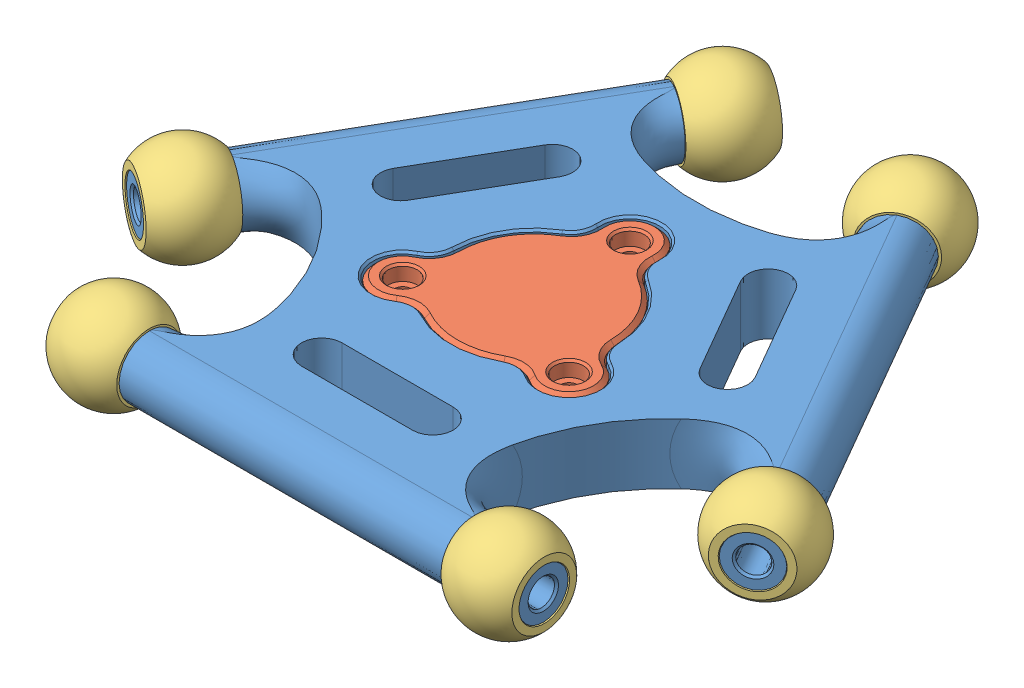
SolidWorks assembly flange, configuration Default. Lengths in mm.
Overall size (140.68 41.57 122.81).
8 component instances, 3 part files, 7 mates.
Components (placement in the parent):
- flange-star-1: flange-star [Default] at origin size (130.67 31.15 114.22)
- calibration-pin-1: calibration-pin [Default] at (0 12 0) x (-1 0 0) z (0 0 1) size (44.16 32 40.5)
- distal-link-sphere-1: distal-link-sphere [Default] at (39.1 5.9539 44.0446) x (0 -0.999016 0.044354) z (0 0.044354 0.999016) size (19 14 19)
- distal-link-sphere-2: distal-link-sphere [Default] at (-39.1 5.9539 44.0446) x (0 -0.979762 0.200167) z (0 0.200167 0.979762) size (19 14 19)
- distal-link-sphere-3: distal-link-sphere [Default] at (57.6937 5.9539 11.8393) x (0.173349 -0.979762 -0.100083) z (0.848499 0.200167 -0.489881) size (19 14 19)
- distal-link-sphere-4: distal-link-sphere [Default] at (-18.5937 5.9539 -55.8839) x (-0.173349 -0.979762 -0.100083) z (-0.848499 0.200167 -0.489881) size (19 14 19)
- distal-link-sphere-5: distal-link-sphere [Default] at (18.5937 5.9539 -55.8839) x (0.038412 -0.999016 -0.022177) z (0.865173 0.044354 -0.499508) size (19 14 19)
- distal-link-sphere-6: distal-link-sphere [Default] at (-57.6937 5.9539 11.8393) x (-0.038412 -0.999016 -0.022177) z (-0.865173 0.044354 -0.499508) size (19 14 19)
Mates (geometry in assembly coordinates):
- Concentric3: concentric: cylinder of flange-star-1 through (0 0 0) axis (0 1 0) radius 11; cylinder of calibration-pin-1 through (0 -5 0) axis (0 1 0) radius 10.875
- Concentric4: concentric: cylinder of flange-star-1 through (16.4545 21.5681 9.5) axis (0 -1 0) radius 1.625; cylinder of calibration-pin-1 through (16.4545 7 9.5) axis (0 1 0) radius 1.625
- Coincident2: coincident: plane of flange-star-1 through (-5.419 7 -18.5519) normal (0 1 0); plane of calibration-pin-1 through (-5.2888 7 -8.9984) normal (0 -1 0)
- Concentric5: concentric: cylinder of flange-star-1 through (45.9 5.9539 44.0446) axis (-1 0 0) radius 4.9; cylinder of distal-link-sphere-1 through (29.6 5.9539 44.0446) axis (1 0 0) radius 5
- Coincident3: coincident: plane of flange-star-1 through (32.1 6 44) normal (1 0 0); plane of distal-link-sphere-1 through (32.1 5.9539 44.0446) normal (-1 0 0)
- Concentric6: concentric: cylinder of flange-star-1 through (-45.9 5.9539 44.0446) axis (1 0 0) radius 4.9; cylinder of distal-link-sphere-2 through (-48.6 5.9539 44.0446) axis (1 0 0) radius 5
- Coincident4: coincident: plane of flange-star-1 through (-32.1 6 44) normal (-1 0 0); plane of distal-link-sphere-2 through (-32.1 5.9539 44.0446) normal (1 0 0)
